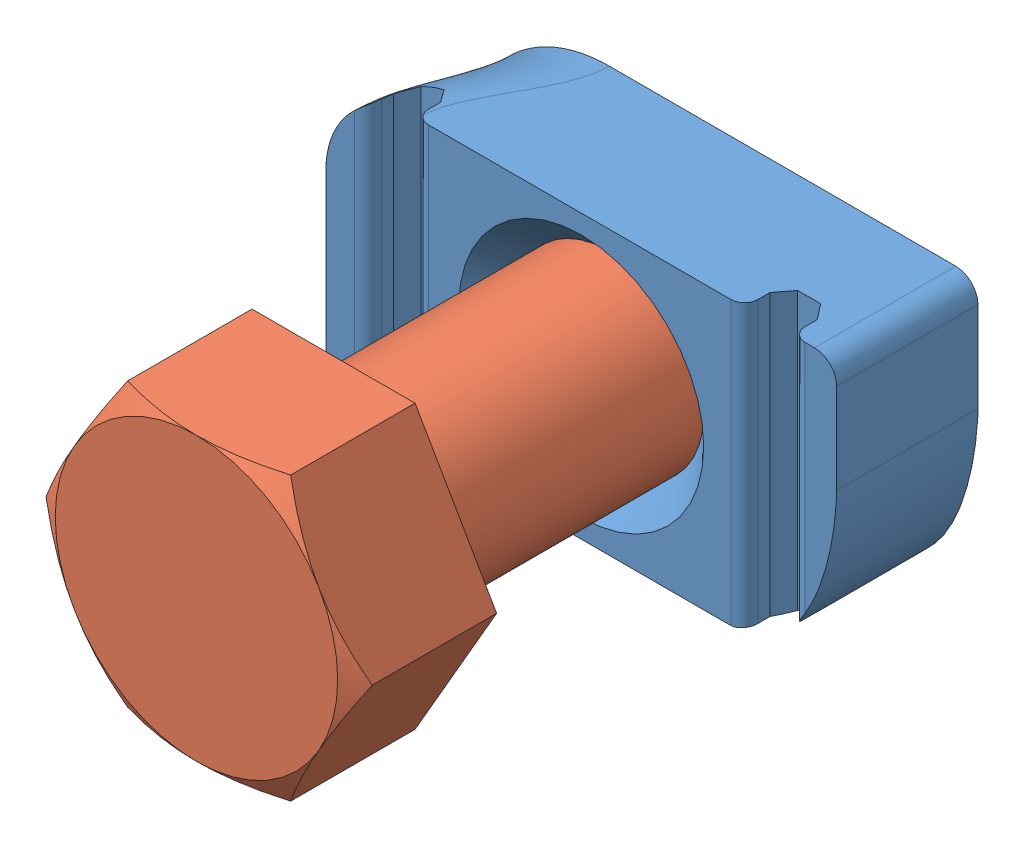
SolidWorks assembly Channel Nut, configuration P2245+P1346. Lengths in mm.
Overall size (34.99 19.63 35.49).
2 component instances, 2 part files, 3 mates.
Components (placement in the parent):
- P3013 - Channel Nut-3: P3013 - Channel Nut [.5"] at origin size (34.99 19.63 9.53)
- hex bolt_ai-1: hex bolt_ai [HBOLT 0.5000-13x1x1-N] at (0 0 25.9549) x (0 0 -1) z (0 -1 0) size (34.65 22 19.05)
Mates (geometry in assembly coordinates):
- Concentric1: concentric aligned: cylinder of P3013 - Channel Nut-3 through (0 0 0) axis (0 0 1) radius 6.35; cylinder of hex bolt_ai-1 through (0 0 25.9549) axis (0 0 1) radius 6.35
- Parallel3: parallel aligned: plane of P3013 - Channel Nut-3 through (-15.7566 -9.525 -9.5305) normal (0 -1 0); plane of hex bolt_ai-1 through (5.4993 -9.525 16.7093) normal (0 -1 0)
- Distance2: distance = 16.7093 mm anti-aligned: plane of hex bolt_ai-1 through (10.9985 0 16.7093) normal (0 0 -1); plane of P3013 - Channel Nut-3 through (-16.725 -9.2176 0) normal (0 0 1)
